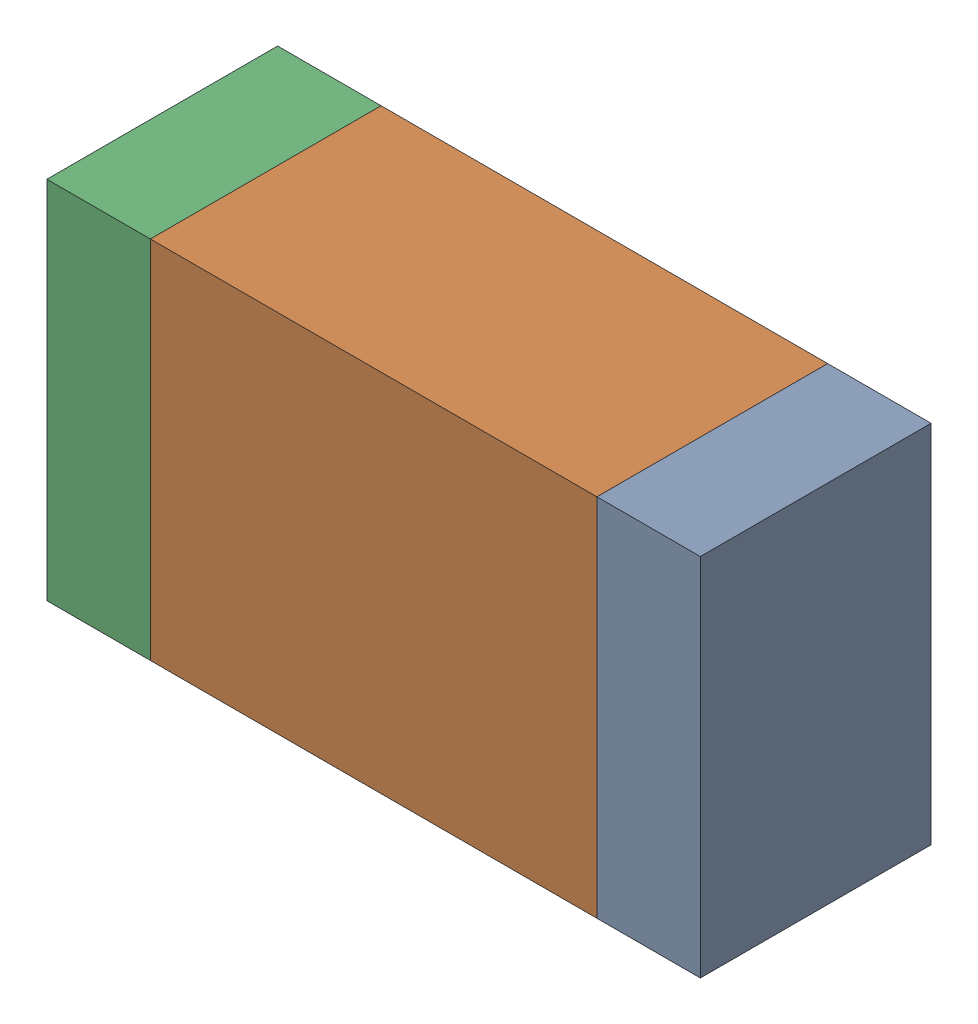
SolidWorks assembly R4, configuration Default. Lengths in mm.
Overall size (1.7 0.95 0.6).
6 component instances, 2 part files, 0 mates.
Components (placement in the parent):
- 959209072-1: 959209072 [Default] at (119.5871 82.2961 0) size (0.27 0.95 0.6)
  - Extruded-21-1: Extruded-21 [Default] at origin size (0.27 0.95 0.6)
- 959209208-1: 959209208 [Default] at (118.8721 82.2961 0) size (1.16 0.95 0.6)
  - Extruded-22-1: Extruded-22 [Default] at origin size (1.16 0.95 0.6)
- 959209072-2: 959209072 [Default] at (118.1571 82.2961 0) size (0.27 0.95 0.6)
  - Extruded-21-1: Extruded-21 [Default] at origin size (0.27 0.95 0.6)
